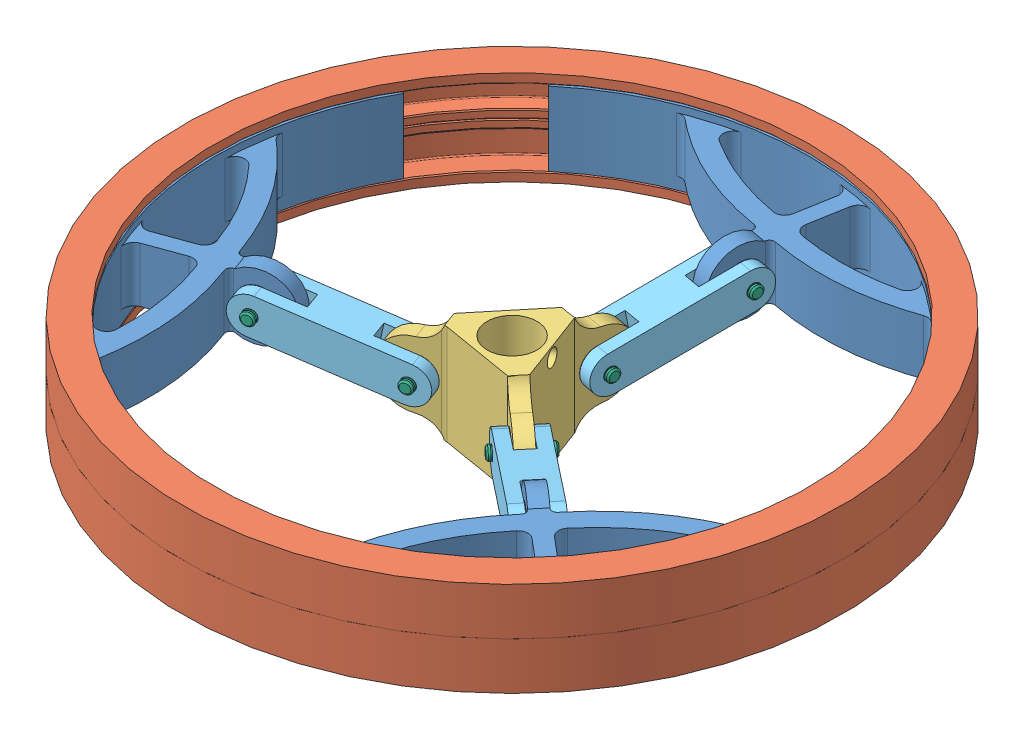
SolidWorks assembly Concept_Assem_2, configuration Default. Lengths in mm.
Overall size (232.03 29.88 232.03).
21 component instances, 6 part files, 20 mates.
Components (placement in the parent):
- Clamp_Ring_Concept-1: Clamp_Ring_Concept [Default] at (-27.5623 8.2477 38.9578) size (92.15 21.41 97.73)
- Ring_Concept-1: Ring_Concept [Default] at (-27.5623 8.3392 38.9578) size (167.64 21.41 167.64)
- Ring_Concept-2: Ring_Concept [Default] at (-73.4072 8.3392 25.3093) x (-0.837169 0 -0.546944) z (-0.546944 0 0.837169) size (167.64 21.41 167.64)
- Clamp_Ring_Concept-2: Clamp_Ring_Concept [Default] at (45.0279 8.2477 -86.7722) x (-0.5 0 -0.866025) z (0.866025 0 -0.5) size (92.15 21.41 97.73)
- Clamp_Ring_Concept-3: Clamp_Ring_Concept [Default] at (-100.1526 8.2477 -86.7722) x (-0.5 0 0.866025) z (-0.866025 0 -0.5) size (92.15 21.41 97.73)
- Carriage-1: Carriage [Default] at (-27.5623 -9.5323 -44.8622) x (0.936847 0 -0.349739) z (0.349739 0 0.936847) size (41.67 25.4 47.99)
- Bearing_RMA-1: Bearing_RMA [2342K61] at (-74.0304 8.8117 -27.7924) x (0.939693 0 -0.34202) z (0.34202 0 0.939693) size (9.53 9.53 3.97)
- Linkage-2: Linkage [Default] at (0.06 0 -0.0715) size (38.12 15.04 34.41)
- Bearing_RMA-2: Bearing_RMA [2342K61] at (10.4545 8.8117 -13.1545) x (-0.766044 0 -0.642788) z (0.642788 0 -0.766044) size (9.53 9.53 3.97)
- Bearing_RMA-3: Bearing_RMA [2342K61] at (-19.1111 8.8117 -93.6395) x (-0.173648 0 0.984808) z (-0.984808 0 -0.173648) size (9.53 9.53 3.97)
- Bearing_RMA-4: Bearing_RMA [2342K61] at (-44.5111 3.1677 -38.5376) x (0.939693 0 -0.34202) z (0.34202 0 0.939693) size (9.53 9.53 3.97)
- Bearing_RMA-5: Bearing_RMA [2342K61] at (-13.6107 3.1677 -33.3464) x (-0.766044 0 -0.642788) z (0.642788 0 -0.766044) size (9.53 9.53 3.97)
- Bearing_RMA-6: Bearing_RMA [2342K61] at (-24.5651 3.1677 -62.7025) x (-0.173648 0 0.984808) z (-0.984808 0 -0.173648) size (9.53 9.53 3.97)
- Linkage-3: Linkage [Default] at (-2.5836 0 -91.1791) x (-0.5 0 -0.866025) z (0.866025 0 -0.5) size (38.12 15.04 34.41)
- Linkage-4: Linkage [Default] at (-80.1633 0 -43.3359) x (-0.5 0 0.866025) z (-0.866025 0 -0.5) size (38.12 15.04 34.41)
- Dowell_Pin_1-1: Dowell_Pin_1 [Default] at (-19.1831 8.8117 -93.6522) x (0.030154 0.984808 -0.17101) z (-0.17101 0.173648 0.969846) size (3.17 13.21 3.17)
- Dowell_Pin_1-2: Dowell_Pin_1 [Default] at (-24.6381 3.1677 -62.7154) x (0.030154 0.984808 -0.17101) z (-0.17101 0.173648 0.969846) size (3.17 13.21 3.17)
- Dowell_Pin_1-3: Dowell_Pin_1 [Default] at (-44.4858 3.1677 -38.468) x (-0.163176 0.984808 0.059391) z (0.925417 0.173648 -0.336824) size (3.17 13.21 3.17)
- Dowell_Pin_1-4: Dowell_Pin_1 [Default] at (-13.5631 3.1677 -33.4031) x (0.133022 0.984808 0.111619) z (-0.754407 0.173648 -0.633022) size (3.17 13.21 3.17)
- Dowell_Pin_1-5: Dowell_Pin_1 [Default] at (-74.0054 8.8117 -27.7238) x (-0.163176 0.984808 0.059391) z (0.925417 0.173648 -0.336824) size (3.17 13.21 3.17)
- Dowell_Pin_1-6: Dowell_Pin_1 [Default] at (10.5015 8.8117 -13.2105) x (0.133022 0.984808 0.111619) z (-0.754407 0.173648 -0.633022) size (3.17 13.21 3.17)
Mates (geometry in assembly coordinates):
- Coincident1: coincident: plane of Ring_Concept-1 through (-27.5623 8.3392 33.5843) normal (0 -1 0); plane of Ring_Concept-2 through (-70.4682 8.3392 20.8108) normal (0 1 0)
- Concentric1: concentric: cylinder of Ring_Concept-1 through (-27.5623 14.3441 -44.8622) axis (0 -1 0) radius 80.82; cylinder of Ring_Concept-2 through (-27.5623 2.3344 -44.8622) axis (0 1 0) radius 80.82
- Parallel1: parallel: cylinder of Clamp_Ring_Concept-1 through (-27.5623 14.2526 -44.8622) axis (0 -1 0) radius 80.1166; cylinder of Ring_Concept-1 through (-27.5623 14.3441 -44.8622) axis (0 -1 0) radius 80.82
- Concentric7: concentric: cone of Clamp_Ring_Concept-1 through (-27.5623 6.1261 -44.8622) axis (0 1 0); cone of Ring_Concept-2 through (-27.5623 6.1261 -44.8622) axis (0 1 0)
- Concentric11: concentric: cylinder of Ring_Concept-2 through (-27.5623 2.3344 -44.8622) axis (0 1 0) radius 80.82; cylinder of Carriage-1 through (-27.5623 3.1677 -44.8622) axis (0 1 0) radius 6.35
- Coincident4: coincident: plane of Clamp_Ring_Concept-2 through (-35.3289 15.8677 -109.4262) normal (0 1 0); plane of Carriage-1 through (-27.5623 15.8677 -44.8622) normal (0 1 0)
- Concentric12: concentric: cylinder of Clamp_Ring_Concept-3 through (-73.3517 8.8117 -25.9277) axis (-0.34202 0 -0.939693) radius 4.699; cylinder of Bearing_RMA-1 through (-73.3517 8.8117 -25.9277) axis (0.34202 0 0.939693) radius 4.7625
- Coincident5: coincident: plane of Clamp_Ring_Concept-3 through (-74.2561 1.8977 -25.5985) normal (0.34202 0 0.939693); plane of Bearing_RMA-1 through (-73.3517 13.3758 -25.9277) normal (0.34202 0 0.939693)
- Concentric13: concentric: cylinder of Carriage-1 through (-45.2224 3.1677 -40.4918) axis (0.34202 0 0.939693) radius 4.6355; cylinder of Bearing_RMA-4 through (-43.8324 3.1677 -36.6729) axis (0.34202 0 0.939693) radius 4.7625
- Coincident6: coincident: plane of Carriage-1 through (-44.0969 17.957 -36.5767) normal (0.34202 0 0.939693); plane of Bearing_RMA-4 through (-43.8324 7.7318 -36.6729) normal (0.34202 0 0.939693)
- Concentric14: concentric: cylinder of Linkage-2 through (13.8485 8.8117 -17.1993) axis (-0.642788 0 0.766044) radius 1.651; cylinder of Bearing_RMA-2 through (11.7301 8.8117 -14.6747) axis (0.642788 0 -0.766044) radius 1.5875
- Parallel4: parallel: plane of Linkage-2 through (13.3492 4.0177 -7.8369) normal (0.642788 0 -0.766044); plane of Bearing_RMA-2 through (9.179 10.5977 -11.6344) normal (-0.642788 0 0.766044)
- Parallel6: parallel: plane of Clamp_Ring_Concept-1 through (12.4674 1.8977 -14.056) normal (0.642788 0 -0.766044); plane of Linkage-2 through (16.1247 4.0177 -11.1446) normal (-0.642788 0 0.766044)
- Concentric15: concentric: cylinder of Linkage-2 through (-10.2161 3.1677 -37.3919) axis (-0.642788 0 0.766044) radius 1.651; cylinder of Bearing_RMA-5 through (-12.3352 3.1677 -34.8665) axis (0.642788 0 -0.766044) radius 1.5875
- Concentric16: concentric: cylinder of Bearing_RMA-3 through (-21.0654 8.8117 -93.9841) axis (-0.984808 0 -0.173648) radius 1.5875; cylinder of Dowell_Pin_1-1 through (-19.1831 8.8117 -93.6522) axis (0.984808 0 0.173648) radius 1.5875
- Coincident11: coincident: plane of Linkage-3 through (-29.766 3.1677 -63.6196) normal (-0.984808 0 -0.173648); plane of Dowell_Pin_1-1 through (-24.3588 7.2484 -94.2849) normal (-0.984808 0 -0.173648)
- Concentric17: concentric: cylinder of Bearing_RMA-6 through (-26.5194 3.1677 -63.0471) axis (-0.984808 0 -0.173648) radius 1.5875; cylinder of Dowell_Pin_1-2 through (-24.6381 3.1677 -62.7154) axis (0.984808 0 0.173648) radius 1.5875
- Coincident12: coincident: plane of Linkage-3 through (-29.766 3.1677 -63.6196) normal (-0.984808 0 -0.173648); plane of Dowell_Pin_1-2 through (-29.8138 1.6043 -63.3481) normal (-0.984808 0 -0.173648)
- Parallel7: parallel: plane of Clamp_Ring_Concept-3 through (-74.2561 1.8977 -25.5985) normal (0.34202 0 0.939693); plane of Linkage-4 through (-78.6061 4.0177 -23.8869) normal (-0.34202 0 -0.939693)
- Parallel8: parallel: plane of Clamp_Ring_Concept-3 through (-75.6461 1.8977 -29.4174) normal (-0.34202 0 -0.939693); plane of Linkage-4 through (-80.0829 4.0177 -27.9444) normal (0.34202 0 0.939693)
